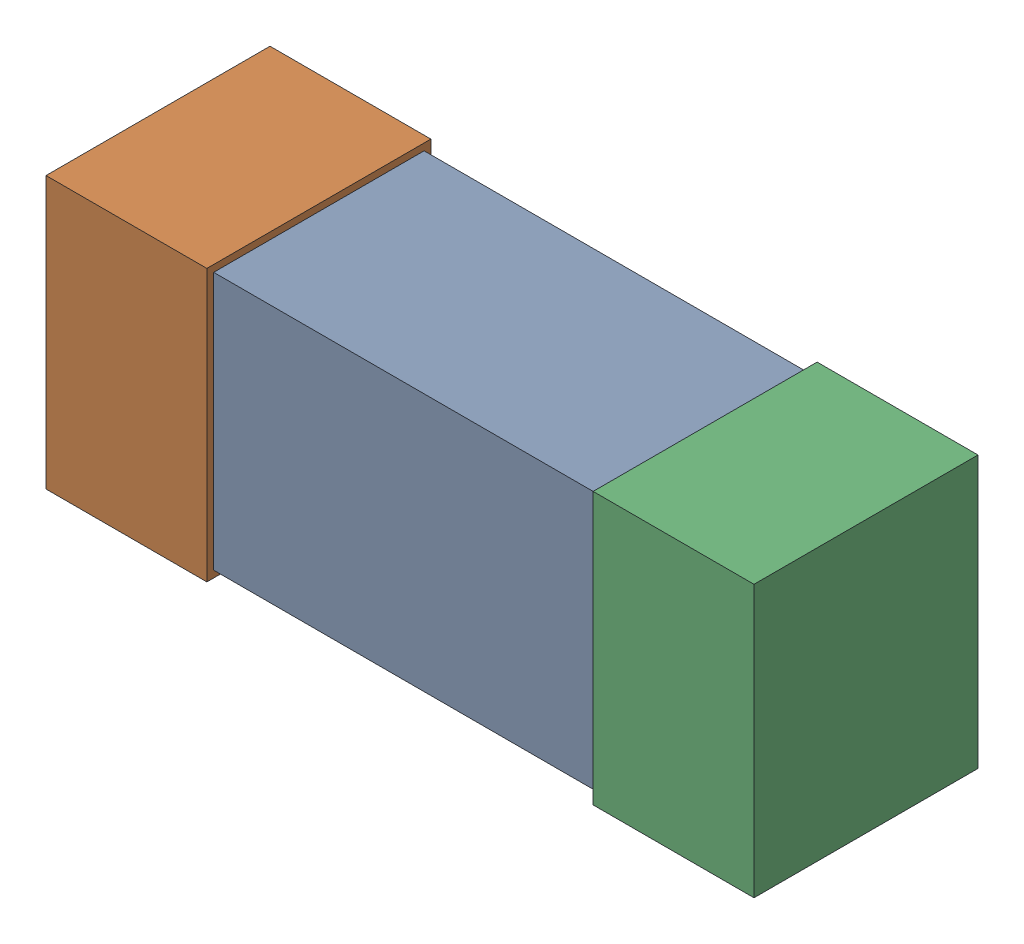
SolidWorks assembly Open CASCADE STEP translator 6.8 1.3.1, configuration Default. Lengths in mm.
Overall size (1.04 0.4 0.33).
3 component instances, 3 part files, 0 mates.
Components (placement in the parent):
- Body_1_3-1: Body_1_3 [Default] at origin size (0.73 0.38 0.31)
- Pin_1-1: Pin_1 [Default] at origin size (0.24 0.4 0.33)
- Pin_2-1: Pin_2 [Default] at (1.506 0 0) x (-1 0 0) z (0 0 1) size (0.24 0.4 0.33)
